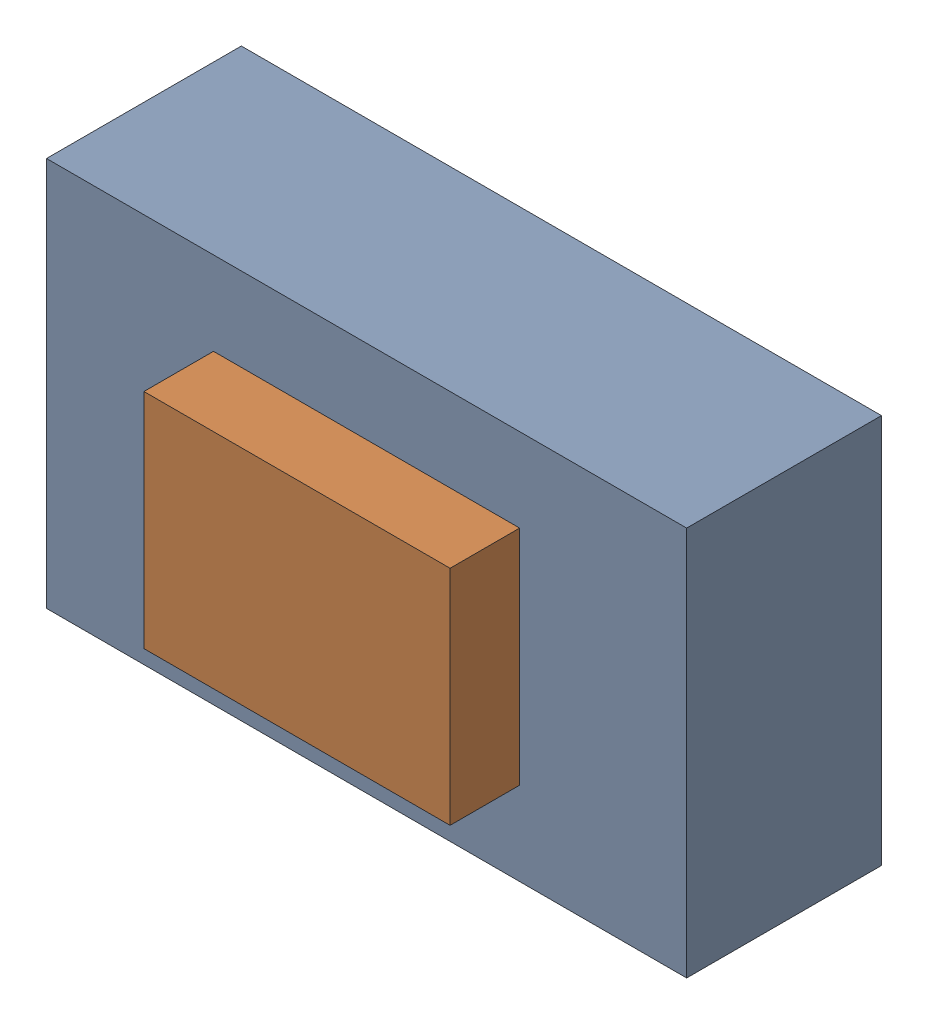
SolidWorks assembly SW1, configuration Default. Lengths in mm.
Overall size (4.6 2.8 1.9).
4 component instances, 2 part files, 0 mates.
Components (placement in the parent):
- 870942880-1: 870942880 [Default] at (36.8293 2.8427 0) size (4.6 2.8 1.4)
  - Extruded_21-1: Extruded_21 [Default] at origin size (4.6 2.8 1.4)
- 870943040-1: 870943040 [Default] at (36.8292 2.8426 1.4) size (2.2 1.6 0.5)
  - Extruded_22-1: Extruded_22 [Default] at origin size (2.2 1.6 0.5)
